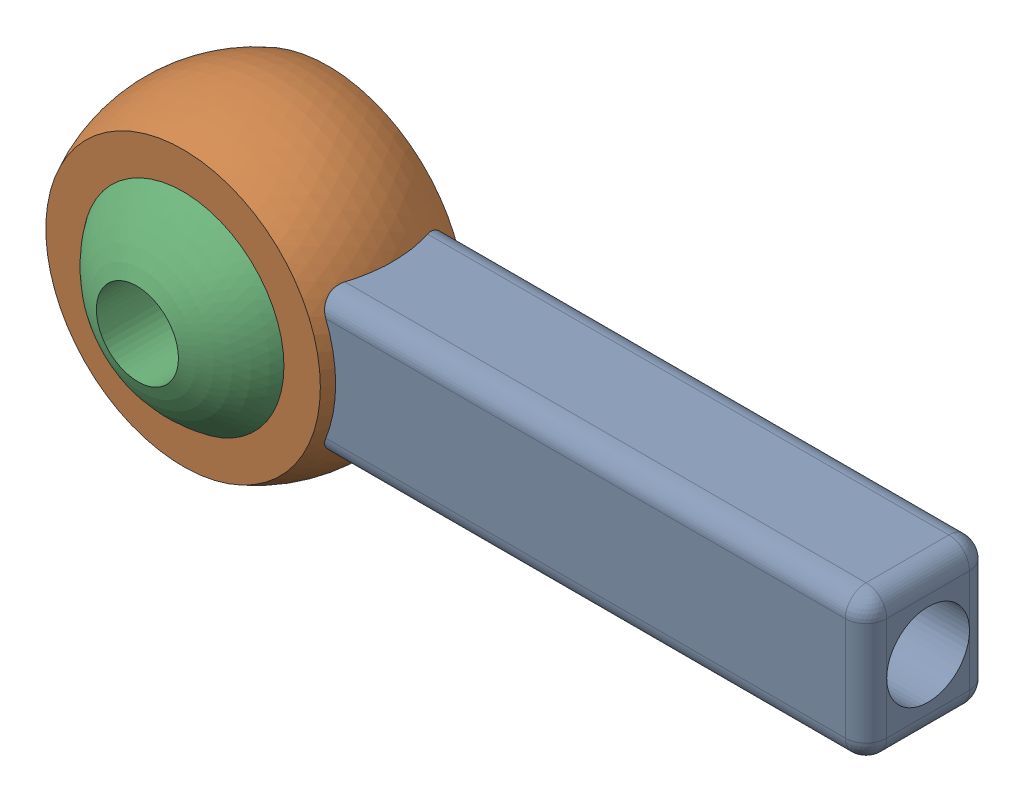
SolidWorks assembly ball head bearing, configuration 默认. Lengths in mm.
Overall size (20.43 8.33 5.74).
2 component instances, 2 part files, 1 mates.
Components (placement in the parent):
- bearing rod-1: bearing rod [默认] at (-7.2585 -0.8884 1.75) size (20 7.5 3.5)
- bearing ball-1: bearing ball [默认] at (-7.2585 -0.8884 1.75) x (0.838746 -0.544504 0.004541) z (0.544445 0.838738 0.009948) size (6 5.66 6)
Mates (geometry in assembly coordinates):
- 同心1: concentric: sphere of 球头轴承杆-1; sphere of 球头轴承球-1
